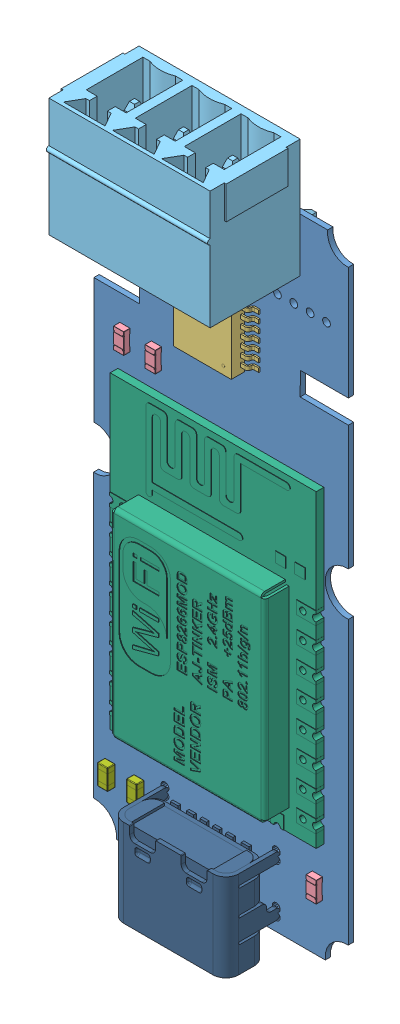
SolidWorks assembly WLED_PCB, configuration Default. Lengths in mm.
Overall size (19.81 55.56 10.7).
27 component instances, 10 part files, 0 mates.
Components (placement in the parent):
- WLED_PCB.step-1: WLED_PCB.step [Default] at origin size (19.81 55.56 10.7)
  - Board.step-1: Board.step [Default] at origin size (19.81 49.2 0.41)
    - Open CASCADE STEP translator 6.8 2.1.1.step-1: Open CASCADE STEP translator 6.8 2.1.1.step [Default] at (0 0 -0.4115) size (19.81 49.2 0.41)
  - U1.step-1: U1.step [Default] at origin size (6.72 7.29 1.82)
    - 5468812944.step-1: 5468812944.step [Default] at (126.825 80.55 -0.4115) x (-1 0 0) z (0 0 -1) size (6.72 7.29 1.82)
  - U3.step-1: U3.step [Default] at origin size (6.6 5.11 1.2)
    - 8882281920.step-1: 8882281920.step [Default] at (126.2 102.875 0) x (-1 0 0) z (0 0 1) size (6.6 5.11 1.2)
  - R3.step-1: R3.step [Default] at origin size (0.81 1.6 0.51)
    - 6233796016.step-1: 6233796016.step [Default] at (133.95 68.4258 0) x (0 1 0) z (0 0 1) size (1.6 0.81 0.51)
  - R2.step-1: R2.step [Default] at origin size (0.81 1.6 0.51)
    - 6233796016.step-1: 6233796016.step [Default] at (119 97.8508 0) x (0 1 0) z (0 0 1) size (1.6 0.81 0.51)
  - R1.step-1: R1.step [Default] at origin size (0.81 1.6 0.51)
    - 6233796016.step-1: 6233796016.step [Default] at (121.45 97.8258 0) x (0 1 0) z (0 0 1) size (1.6 0.81 0.51)
  - P2.step-1: P2.step [Default] at origin size (12.82 9.2 10.7)
    - terminal_blocks_a-tb381-oq03ch.step-1: terminal_blocks_a-tb381-oq03ch.step [Default] at (126.3502 117.974 0) x (-1 0 0) z (0 1 0) size (12.82 10.7 9.2)
  - M1.step-1: M1.step [Default] at origin size (16.01 24.01 2.69)
    - User_Library-EPS8266_ESP-12E.step-1: User_Library-EPS8266_ESP-12E.step [Default] at (126.4501 83.4752 0) x (0 1 0) z (0 0 1) size (24 16.01 2.69)
  - C6.step-1: C6.step [Default] at origin size (0.8 1.6 0.6)
    - 6233794896.step-1: 6233794896.step [Default] at (117.8499 67.9759 0) x (0 1 0) z (0 0 1) size (1.6 0.8 0.6)
  - C5.step-1: C5.step [Default] at origin size (0.8 1.6 0.6)
    - 6233794896.step-1: 6233794896.step [Default] at (120.0999 68.0009 0) x (0 1 0) z (0 0 1) size (1.6 0.8 0.6)
  - C4.step-1: C4.step [Default] at origin size (1.6 0.8 0.6)
    - 6233800176.step-1: 6233800176.step [Default] at (123.6509 74.8249 -0.4115) x (1 0 0) z (0 0 -1) size (1.6 0.8 0.6)
  - C2.step-1: C2.step [Default] at origin size (1.6 0.8 0.6)
    - 6233794736.step-1: 6233794736.step [Default] at (127.9491 74.8501 -0.4115) x (-1 0 0) z (0 0 -1) size (1.6 0.8 0.6)
  - P1.step-1: P1.step [Default] at origin size (8.97 6.83 4.32)
    - User_Library-USB_Type_C_6pin.step-1: User_Library-USB_Type_C_6pin.step [Default] at (126.3595 65.7769 0) x (0 1 0) z (0 0 1) size (6.83 8.97 4.32)
